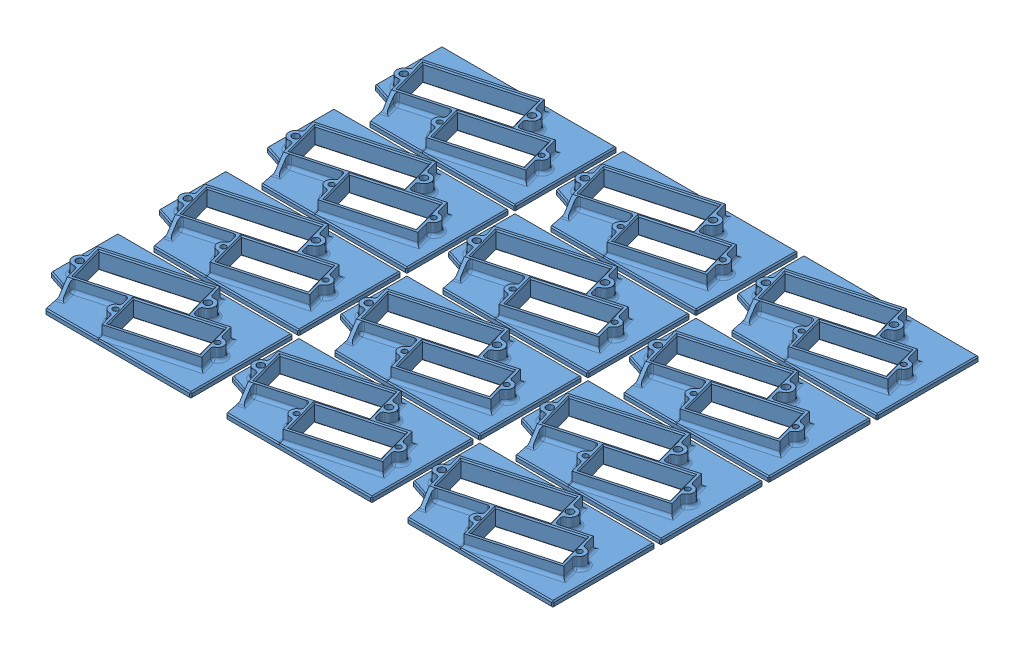
SolidWorks assembly RadianServoTray-Plate, configuration Default. Lengths in mm.
Overall size (185 6.13 176.06).
12 component instances, 1 part files, 3 mates.
Components (placement in the parent):
- Servo Tray-1: Servo Tray [Default] at (60 0 -35) x (1 0 0) z (0 0 -1) size (60 6.13 35.06)
- Servo Tray-3: Servo Tray [Default] at (60 0 -72) x (1 0 0) z (0 0 -1) size (60 6.13 35.06)
- Servo Tray-4: Servo Tray [Default] at (60 0 -109) x (1 0 0) z (0 0 -1) size (60 6.13 35.06)
- Servo Tray-5: Servo Tray [Default] at (60 0 -146) x (1 0 0) z (0 0 -1) size (60 6.13 35.06)
- Servo Tray-6: Servo Tray [Default] at (122 0 -35) x (1 0 0) z (0 0 -1) size (60 6.13 35.06)
- Servo Tray-7: Servo Tray [Default] at (122 0 -72) x (1 0 0) z (0 0 -1) size (60 6.13 35.06)
- Servo Tray-8: Servo Tray [Default] at (122 0 -109) x (1 0 0) z (0 0 -1) size (60 6.13 35.06)
- Servo Tray-9: Servo Tray [Default] at (122 0 -146) x (1 0 0) z (0 0 -1) size (60 6.13 35.06)
- Servo Tray-14: Servo Tray [Default] at (184 0 -35) x (1 0 0) z (0 0 -1) size (60 6.13 35.06)
- Servo Tray-15: Servo Tray [Default] at (184 0 -72) x (1 0 0) z (0 0 -1) size (60 6.13 35.06)
- Servo Tray-16: Servo Tray [Default] at (184 0 -109) x (1 0 0) z (0 0 -1) size (60 6.13 35.06)
- Servo Tray-17: Servo Tray [Default] at (184 0 -146) x (1 0 0) z (0 0 -1) size (60 6.13 35.06)
Mates (geometry in assembly coordinates):
- Coincident1: coincident: point of Servo Tray-1; point of assembly
- Coincident3: coincident anti-aligned: plane of Servo Tray-1 through (60 0 -35) normal (0 -1 0); plane of assembly through (0 0 0) normal (0 1 0)
- Coincident5: coincident: line of Servo Tray-1 through (60 0 0) axis (-1 0 0); plane of assembly
